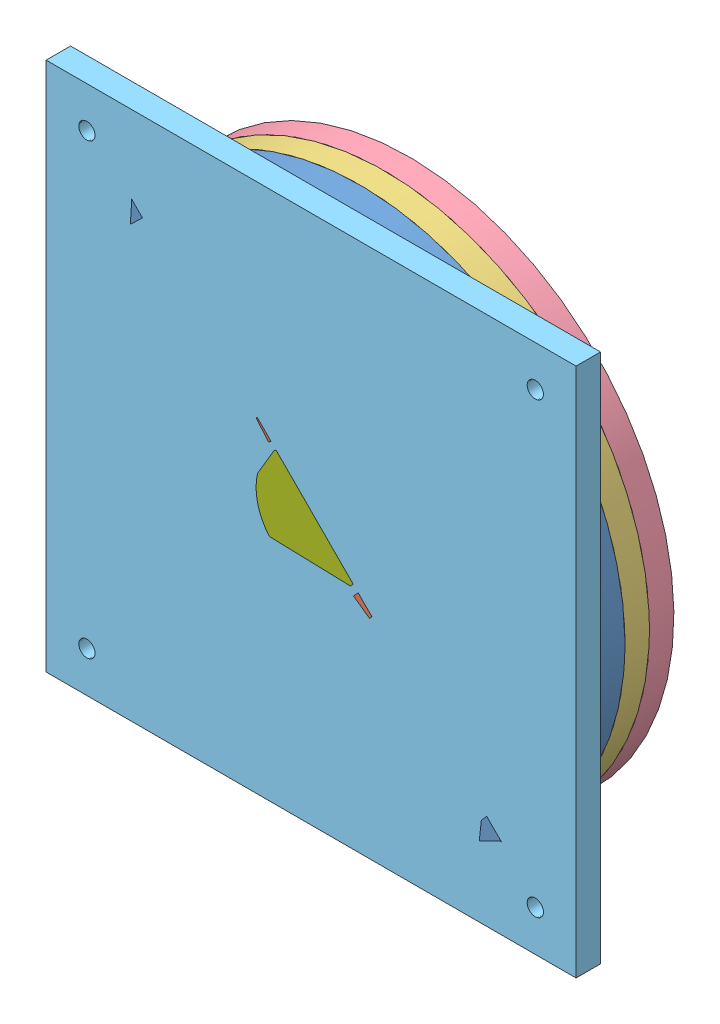
SolidWorks assembly v4, configuration Default. Lengths in mm.
Overall size (168.34 168.34 133.25).
11 component instances, 8 part files, 20 mates.
Components (placement in the parent):
- middle_ring_outer-1: middle_ring_outer [Default] at (-44.2635 -92.51 -38.9874) x (0.998848 -0.047991 0) z (0 0 1) size (130 130 6)
- middle_ring_inner-1: middle_ring_inner [Default] at (-44.2635 -92.51 -38.9874) size (40 40 6)
- top-1: top [Default] at (-44.2635 -92.51 -44.9874) size (130 130 6)
- floater_top-1: floater_top [Default] at (-44.2635 -92.51 -44.9874) x (-0.363238 -0.931696 0) z (0 0 -1) size (130 130 6)
- square base-1: square base [Default] at (-44.2635 -92.51 -32.9874) size (130 130 100)
- midlle_ring_inner_hollow-1: midlle_ring_inner_hollow [Default] at (-44.2635 -92.51 -44.9874) size (27 27 6)
- floater_lat_stabilizer-2: floater_lat_stabilizer [Default] at (-44.2635 -92.51 -38.9874) size (27 27 6)
- floater_lat_stabilizer-3: floater_lat_stabilizer [Default] at (-44.2635 -92.51 -32.9874) size (27 27 6)
- middle_ring_outer-3: middle_ring_outer [Default] at (-44.2635 -92.51 -32.9874) size (130 130 6)
- middle_ring_inner-2: middle_ring_inner [Default] at (-44.2635 -92.51 -32.9874) size (40 40 6)
- flip side stabilizer fat-1: flip side stabilizer fat [Default] at (-44.2635 -92.51 -66.2374) size (29.5 29.5 15.25)
Mates (geometry in assembly coordinates):
- Coincident3: coincident anti-aligned: plane of middle_ring_outer-1 through (-44.2635 -92.51 -38.9874) normal (0 0 -1); plane of top-1 through (-44.2635 -92.51 -38.9874) normal (0 0 1)
- Concentric3: concentric anti-aligned: circle of middle_ring_outer-1; cylinder of top-1 through (-44.2635 -92.51 -38.9874) axis (0 0 -1) radius 65
- Concentric5: concentric anti-aligned: cylinder of top-1 through (-44.2635 -92.51 -38.9874) axis (0 0 -1) radius 65; cylinder of floater_top-1 through (-44.2635 -92.51 -50.9874) axis (0 0 1) radius 65
- Concentric6: concentric aligned: cylinder of middle_ring_outer-1 through (-44.2635 -92.51 -32.9874) axis (0 0 -1) radius 65; circle of square base-1
- Concentric7: concentric aligned: cylinder of middle_ring_outer-1 through (-44.2635 -92.51 -32.9874) axis (0 0 -1) radius 65; cylinder of middle_ring_inner-1 through (-44.2635 -92.51 -32.9874) axis (0 0 -1) radius 20
- Coincident6: coincident anti-aligned: plane of middle_ring_inner-1 through (-44.2635 -92.51 -38.9874) normal (0 0 -1); plane of top-1 through (-44.2635 -92.51 -38.9874) normal (0 0 1)
- Concentric8: concentric anti-aligned: cylinder of floater_top-1 through (-44.2635 -92.51 -50.9874) axis (0 0 1) radius 65; cylinder of midlle_ring_inner_hollow-1 through (-44.2635 -92.51 -38.9874) axis (0 0 -1) radius 13.5
- Coincident7: coincident anti-aligned: plane of floater_top-1 through (-44.2635 -92.51 -44.9874) normal (0 0 1); circle of midlle_ring_inner_hollow-1
- Concentric9: concentric aligned: cylinder of midlle_ring_inner_hollow-1 through (-44.2635 -92.51 -38.9874) axis (0 0 -1) radius 13.5; cylinder of floater_lat_stabilizer-2 through (-44.2635 -92.51 -32.9874) axis (0 0 -1) radius 13.5
- Coincident8: coincident anti-aligned: plane of midlle_ring_inner_hollow-1 through (-44.2635 -92.51 -38.9874) normal (0 0 1); plane of floater_lat_stabilizer-2 through (-44.2635 -92.51 -38.9874) normal (0 0 -1)
- Concentric10: concentric aligned: cylinder of floater_lat_stabilizer-2 through (-44.2635 -92.51 -32.9874) axis (0 0 -1) radius 13.5; cylinder of floater_lat_stabilizer-3 through (-44.2635 -92.51 -26.9874) axis (0 0 -1) radius 13.5
- Coincident9: coincident anti-aligned: plane of floater_lat_stabilizer-2 through (-44.2635 -92.51 -32.9874) normal (0 0 1); plane of floater_lat_stabilizer-3 through (-44.2635 -92.51 -32.9874) normal (0 0 -1)
- Concentric12: concentric aligned: cylinder of middle_ring_outer-1 through (-44.2635 -92.51 -32.9874) axis (0 0 -1) radius 65; cylinder of middle_ring_outer-3 through (-44.2635 -92.51 -26.9874) axis (0 0 -1) radius 65
- Coincident11: coincident anti-aligned: plane of middle_ring_outer-1 through (-44.2635 -92.51 -32.9874) normal (0 0 1); plane of middle_ring_outer-3 through (-44.2635 -92.51 -32.9874) normal (0 0 -1)
- Concentric13: concentric aligned: cylinder of middle_ring_inner-1 through (-44.2635 -92.51 -32.9874) axis (0 0 -1) radius 20; cylinder of middle_ring_inner-2 through (-44.2635 -92.51 -26.9874) axis (0 0 -1) radius 20
- Coincident12: coincident anti-aligned: plane of middle_ring_inner-1 through (-44.2635 -92.51 -32.9874) normal (0 0 1); plane of middle_ring_inner-2 through (-44.2635 -92.51 -32.9874) normal (0 0 -1)
- Coincident14: coincident aligned: plane of square base-1 through (20.7365 -27.51 -26.9874) normal (0 0 1); plane of middle_ring_outer-3 through (-44.2635 -92.51 -26.9874) normal (0 0 1)
- Concentric15: concentric anti-aligned: cylinder of floater_top-1 through (-44.2635 -92.51 -50.9874) axis (0 0 1) radius 65; cylinder of flip side stabilizer fat-1 through (-44.2635 -92.51 -50.9874) axis (0 0 -1) radius 14.75
- Coincident15: coincident anti-aligned: plane of floater_top-1 through (-44.2635 -92.51 -50.9874) normal (0 0 -1); plane of flip side stabilizer fat-1 through (-44.2635 -92.51 -50.9874) normal (0 0 1)
- Coincident16: coincident anti-aligned: plane of top-1 through (-44.2635 -92.51 -44.9874) normal (0 0 -1); plane of floater_top-1 through (-44.2635 -92.51 -44.9874) normal (0 0 1)
